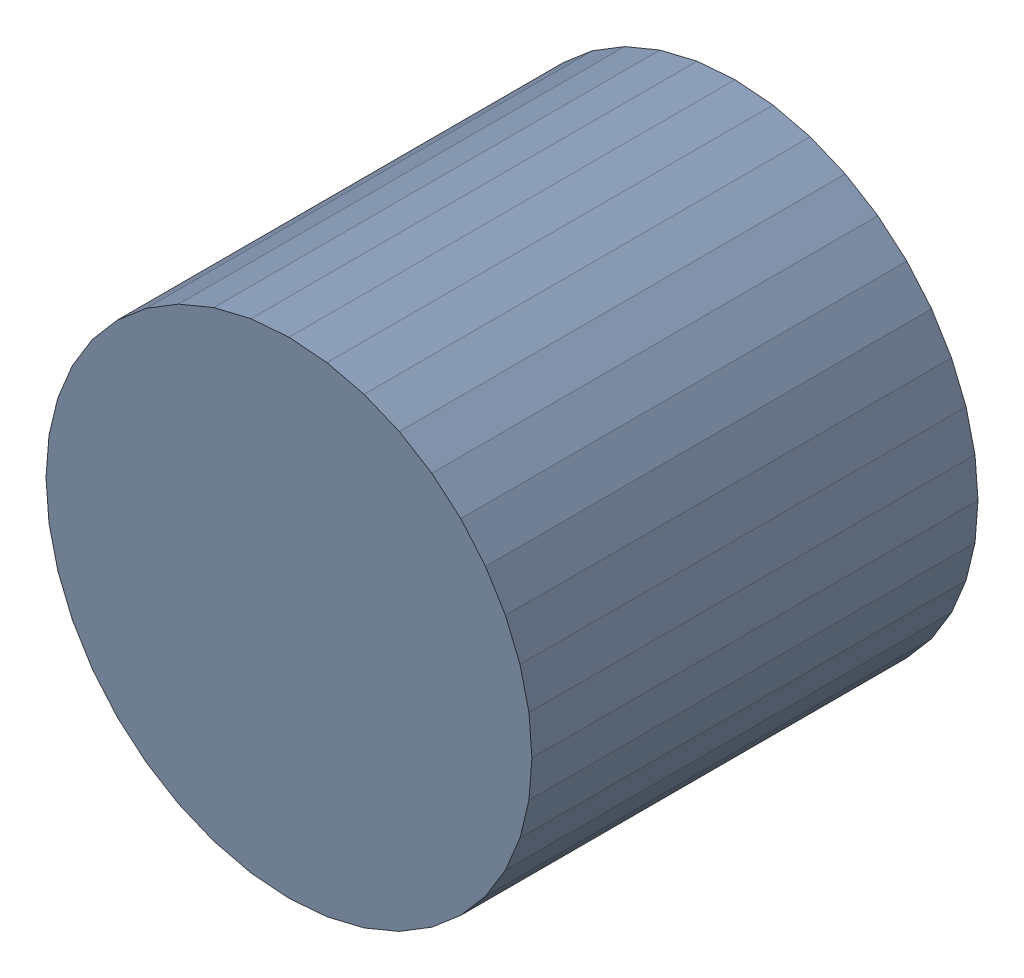
SolidWorks assembly USB45_C7, configuration Default. Lengths in mm.
Overall size (6.32 6.32 5.8).
2 component instances, 1 part files, 0 mates.
Components (placement in the parent):
- 384312384-1: 384312384 [Default] at (149.86 41.275 -6.9024) size (6.32 6.32 5.8)
  - Extruded_7-1: Extruded_7 [Default] at origin size (6.32 6.32 5.8)
